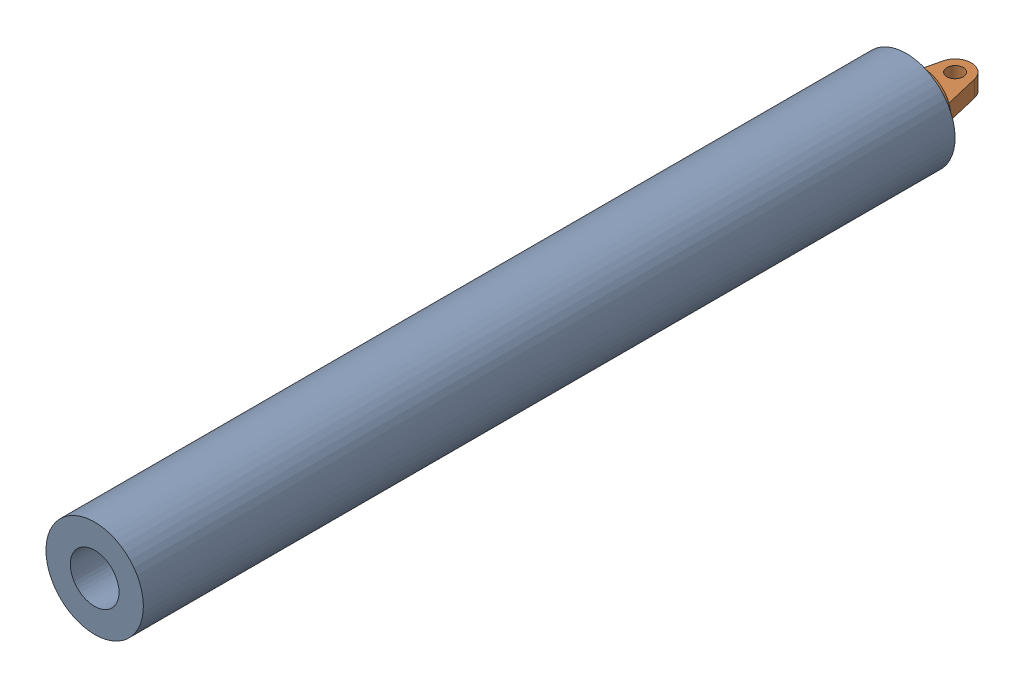
SolidWorks assembly 电推杆下部, configuration 默认. Lengths in mm.
Overall size (78.34 78.34 540).
2 component instances, 2 part files, 5 mates.
Components (placement in the parent):
- 电推杆1-1: 电推杆1 [默认] at (338.7336 -236.5213 0) x (0.924559 0.381038 0) z (0 0 1) size (60 60 500)
- 电推杆接头-1: 电推杆接头 [默认] at (-4.4626 -5 275.1641) x (1 0 0) z (0 1 0) size (35 40 35)
Mates (geometry in assembly coordinates):
- 重合1: coincident anti-aligned: plane of 电推杆1-1 through (0 0 -140.6817) normal (0 0 -1); plane of 电推杆接头-1 through (0 0 -140.6817) normal (0 0 1)
- 同心1: concentric aligned: cylinder of 电推杆1-1 through (0 0 359.3183) axis (0 0 -1) radius 30; cylinder of 电推杆接头-1 through (0 0 -140.6817) axis (0 0 -1) radius 17.5
- 对称1: symmetric aligned: plane of 电推杆接头-1 through (-4.4626 -5 134.4823) normal (0 -1 0); plane of 电推杆接头-1 through (-4.4626 5 134.4823) normal (0 1 0)
- 对称2: symmetric aligned: line of 电推杆接头-1 through (15 5 -150.6817) axis (0 -1 0); line of 电推杆接头-1 through (-15 5 -150.6817) axis (0 -1 0)
- 重合2: coincident anti-aligned: plane of 电推杆1-1 through (0 0 -140.6817) normal (0 0 -1)
